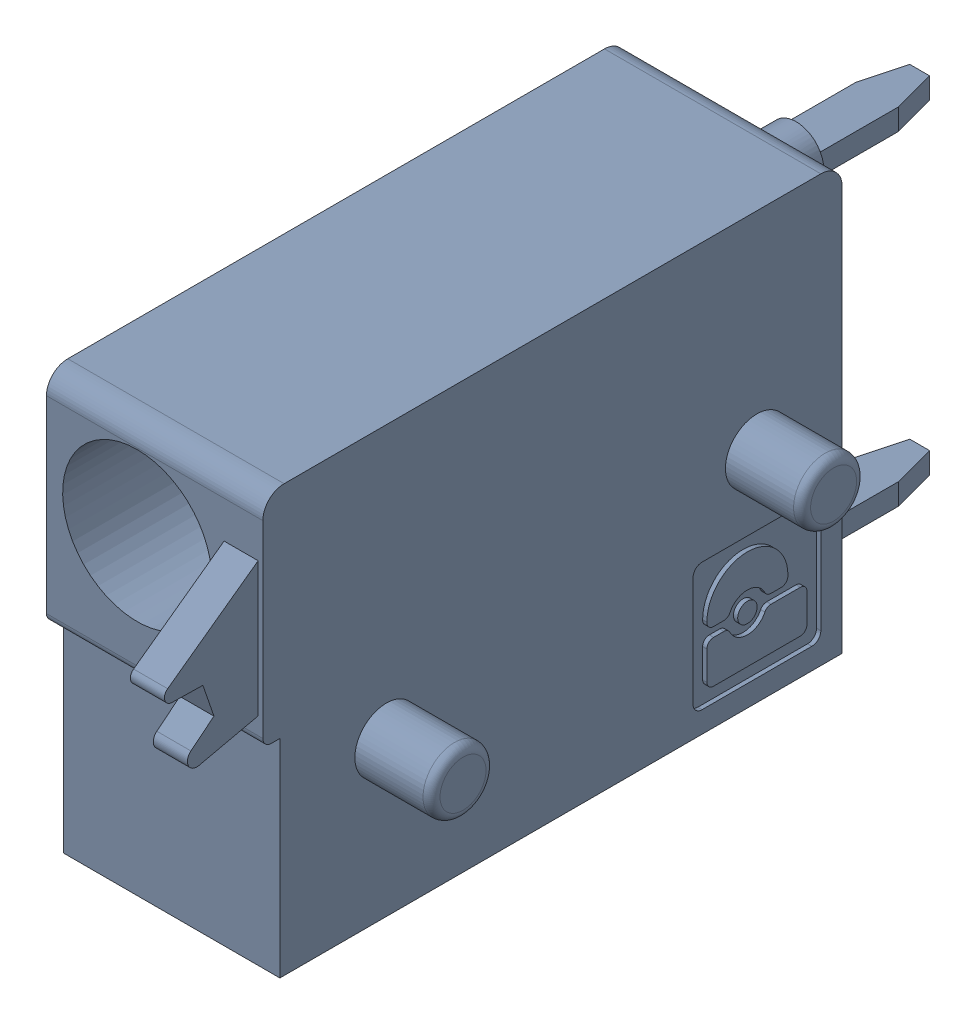
SolidWorks assembly J10, configuration Default. Lengths in mm.
Overall size (6.88 10 19.2).
2 component instances, 1 part files, 0 mates.
Components (placement in the parent):
- 1790348-1: 1790348 [Default] at (19.6851 -7.6199 0) x (0 1 0) z (1 0 0) size (10 19.2 6.88)
  - ffkds-v2-5.08-1: ffkds-v2-5.08 [Default] at (-23.7414 -38.158 -2.54) x (0 -1 0) z (0 0 1) size (19.2 10 6.88)
